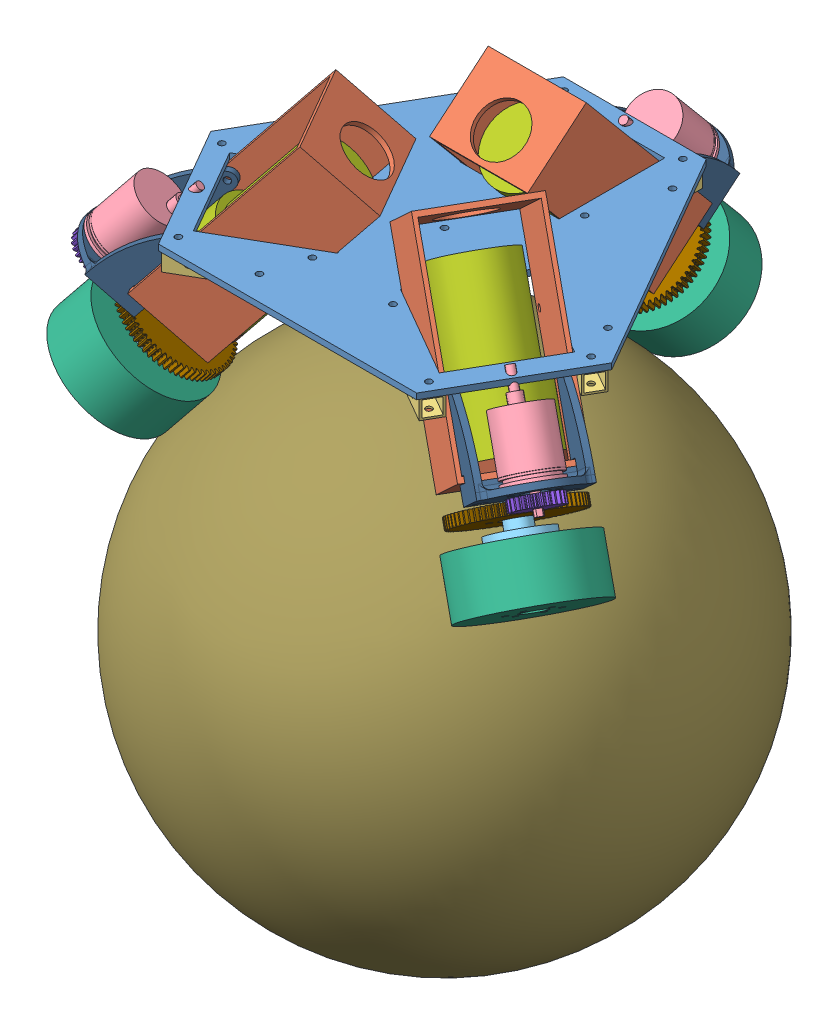
SolidWorks assembly 玉乗りロボット, configuration ﾃﾞﾌｫﾙﾄ. Lengths in mm.
Overall size (412.44 432.36 384.3).
38 component instances, 12 part files, 13 mates.
Components (placement in the parent):
- 土台1段目板-1: 土台1段目板 [ﾃﾞﾌｫﾙﾄ] at (0 175.0271 0) x (-0.5 0 -0.866025) z (0 1 0) size (204.33 176.96 3)
- 脚ユニット-1: 脚ユニット [ﾃﾞﾌｫﾙﾄ] at (4.0472 123.7086 71.2224) x (-0.55667 0.766044 -0.321394) z (0.5 0 -0.866025) size (148.1 79.92 70.5)
  - モータエンコーダ取り付け角柱-1: モータエンコーダ取り付け角柱 [ﾃﾞﾌｫﾙﾄ] at (20.22 50.0169 59.6568) x (1 0 0) z (0 -1 0) size (100 50 39)
  - 土台と脚取り付け角柱-1: 土台と脚取り付け角柱 [ﾃﾞﾌｫﾙﾄ] at (18.0757 50.5169 29.4068) x (0.766044 0.642788 0) z (0.642788 -0.766044 0) size (10 10 60)
  - 土台と脚取り付け角柱-2: 土台と脚取り付け角柱 [ﾃﾞﾌｫﾙﾄ] at (18.0757 50.5169 89.9068) x (0.766044 0.642788 0) z (0.642788 -0.766044 0) size (10 10 60)
  - E6A2_CW3C-1: E6A2_CW3C [ﾃﾞﾌｫﾙﾄ] at (-34.78 82.1169 68.6568) x (0 0 1) z (-1 0 0) size (25 25 56.5)
  - オムニ用ハブ-1: オムニ用ハブ [ﾃﾞﾌｫﾙﾄ] at (-52.28 45.5169 59.6568) x (1 0 0) z (0 -0.475862 0.87952) size (16 28 28)
  - オムニホイール-1: オムニホイール [ﾃﾞﾌｫﾙﾄ] at (-52.28 45.5169 59.6568) x (-1 0 0) z (0 -0.027652 -0.999618) size (25.6 60 60)
  - モータ_ツカサ電工-1: モータ_ツカサ電工 [ﾃﾞﾌｫﾙﾄ] at (9.22 45.5169 59.6568) x (0 0 -1) z (-1 0 0) size (43 43 101)
  - エンコーダ歯車-1: エンコーダ歯車 [デフォルト] at (-38.78 82.1169 59.6568) x (0 0.046374 -0.998924) z (1 0 0) size (22.4 22.38 5)
  - モータ伝達歯車-1: モータ伝達歯車 [アクリル切り出し] at (-41.28 45.5169 59.6568) x (0 0.999618 -0.027652) z (-1 0 0) size (53.59 53.59 5)
  - エンコーダ取付3D部品-1: エンコーダ取付3D部品 [ﾃﾞﾌｫﾙﾄ] at (-37.78 45.7169 59.6568) x (0 0 1) z (-1 0 0) size (44.6 34 47)
  - モータ取り付けアクリル板-1: モータ取り付けアクリル板 [ﾃﾞﾌｫﾙﾄ] at (-27.28 45.5169 59.6568) x (0 -0.866025 -0.5) z (1 0 0) size (43 43 5)
- 脚ユニット-2: 脚ユニット [ﾃﾞﾌｫﾙﾄ] at (59.6568 123.7086 -39.1162) x (0 0.766044 0.642788) z (-1 0 0) size (148.1 79.92 70.5)
  - モータエンコーダ取り付け角柱-1: モータエンコーダ取り付け角柱 [ﾃﾞﾌｫﾙﾄ] at (20.22 50.0169 59.6568) x (1 0 0) z (0 -1 0) size (100 50 39)
  - 土台と脚取り付け角柱-1: 土台と脚取り付け角柱 [ﾃﾞﾌｫﾙﾄ] at (18.0757 50.5169 29.4068) x (0.766044 0.642788 0) z (0.642788 -0.766044 0) size (10 10 60)
  - 土台と脚取り付け角柱-2: 土台と脚取り付け角柱 [ﾃﾞﾌｫﾙﾄ] at (18.0757 50.5169 89.9068) x (0.766044 0.642788 0) z (0.642788 -0.766044 0) size (10 10 60)
  - E6A2_CW3C-1: E6A2_CW3C [ﾃﾞﾌｫﾙﾄ] at (-34.78 82.1169 68.6568) x (0 0 1) z (-1 0 0) size (25 25 56.5)
  - オムニ用ハブ-1: オムニ用ハブ [ﾃﾞﾌｫﾙﾄ] at (-52.28 45.5169 59.6568) x (1 0 0) z (0 -0.475862 0.87952) size (16 28 28)
  - オムニホイール-1: オムニホイール [ﾃﾞﾌｫﾙﾄ] at (-52.28 45.5169 59.6568) x (-1 0 0) z (0 -0.027652 -0.999618) size (25.6 60 60)
  - モータ_ツカサ電工-1: モータ_ツカサ電工 [ﾃﾞﾌｫﾙﾄ] at (9.22 45.5169 59.6568) x (0 0 -1) z (-1 0 0) size (43 43 101)
  - エンコーダ歯車-1: エンコーダ歯車 [デフォルト] at (-38.78 82.1169 59.6568) x (0 0.046374 -0.998924) z (1 0 0) size (22.4 22.38 5)
  - モータ伝達歯車-1: モータ伝達歯車 [アクリル切り出し] at (-41.28 45.5169 59.6568) x (0 0.999618 -0.027652) z (-1 0 0) size (53.59 53.59 5)
  - エンコーダ取付3D部品-1: エンコーダ取付3D部品 [ﾃﾞﾌｫﾙﾄ] at (-37.78 45.7169 59.6568) x (0 0 1) z (-1 0 0) size (44.6 34 47)
  - モータ取り付けアクリル板-1: モータ取り付けアクリル板 [ﾃﾞﾌｫﾙﾄ] at (-27.28 45.5169 59.6568) x (0 -0.866025 -0.5) z (1 0 0) size (43 43 5)
- 脚ユニット-3: 脚ユニット [ﾃﾞﾌｫﾙﾄ] at (-63.704 123.7086 -32.1063) x (0.55667 0.766044 -0.321394) z (0.5 0 0.866025) size (148.1 79.92 70.5)
  - モータエンコーダ取り付け角柱-1: モータエンコーダ取り付け角柱 [ﾃﾞﾌｫﾙﾄ] at (20.22 50.0169 59.6568) x (1 0 0) z (0 -1 0) size (100 50 39)
  - 土台と脚取り付け角柱-1: 土台と脚取り付け角柱 [ﾃﾞﾌｫﾙﾄ] at (18.0757 50.5169 29.4068) x (0.766044 0.642788 0) z (0.642788 -0.766044 0) size (10 10 60)
  - 土台と脚取り付け角柱-2: 土台と脚取り付け角柱 [ﾃﾞﾌｫﾙﾄ] at (18.0757 50.5169 89.9068) x (0.766044 0.642788 0) z (0.642788 -0.766044 0) size (10 10 60)
  - E6A2_CW3C-1: E6A2_CW3C [ﾃﾞﾌｫﾙﾄ] at (-34.78 82.1169 68.6568) x (0 0 1) z (-1 0 0) size (25 25 56.5)
  - オムニ用ハブ-1: オムニ用ハブ [ﾃﾞﾌｫﾙﾄ] at (-52.28 45.5169 59.6568) x (1 0 0) z (0 -0.475862 0.87952) size (16 28 28)
  - オムニホイール-1: オムニホイール [ﾃﾞﾌｫﾙﾄ] at (-52.28 45.5169 59.6568) x (-1 0 0) z (0 -0.027652 -0.999618) size (25.6 60 60)
  - モータ_ツカサ電工-1: モータ_ツカサ電工 [ﾃﾞﾌｫﾙﾄ] at (9.22 45.5169 59.6568) x (0 0 -1) z (-1 0 0) size (43 43 101)
  - エンコーダ歯車-1: エンコーダ歯車 [デフォルト] at (-38.78 82.1169 59.6568) x (0 0.046374 -0.998924) z (1 0 0) size (22.4 22.38 5)
  - モータ伝達歯車-1: モータ伝達歯車 [アクリル切り出し] at (-41.28 45.5169 59.6568) x (0 0.999618 -0.027652) z (-1 0 0) size (53.59 53.59 5)
  - エンコーダ取付3D部品-1: エンコーダ取付3D部品 [ﾃﾞﾌｫﾙﾄ] at (-37.78 45.7169 59.6568) x (0 0 1) z (-1 0 0) size (44.6 34 47)
  - モータ取り付けアクリル板-1: モータ取り付けアクリル板 [ﾃﾞﾌｫﾙﾄ] at (-27.28 45.5169 59.6568) x (0 -0.866025 -0.5) z (1 0 0) size (43 43 5)
- 球-1: 球 [ﾃﾞﾌｫﾙﾄ] x (0.798586 0.538291 0.269265) z (-0.428264 0.193852 0.882616) size (250 250 250)
Mates (geometry in assembly coordinates):
- 同心円1: concentric: circle of 土台1段目板-1; circle of 脚ユニット-1/土台と脚取り付け角柱-2
- 平行1: parallel: line of 土台1段目板-1 through (87.9306 178.0271 21.6106) axis (-0.866025 0 -0.5); line of 脚ユニット-1/土台と脚取り付け角柱-2 through (48.9712 175.0271 -12.4296) axis (0.866025 0 0.5)
- 同心円2: concentric: circle of 土台1段目板-1; circle of 脚ユニット-2/土台と脚取り付け角柱-2
- 平行2: parallel: line of 土台1段目板-1 through (-25.25 178.0271 -86.9554) axis (0 0 1); line of 脚ユニット-2/土台と脚取り付け角柱-2 through (-35.25 175.0271 -36.1955) axis (0 0 -1)
- 同心円3: concentric: circle of 土台1段目板-1; circle of 脚ユニット-3/土台と脚取り付け角柱-2
- 平行3: parallel: line of 土台1段目板-1 through (-62.6806 178.0271 65.3449) axis (0.866025 0 -0.5); line of 脚ユニット-3/土台と脚取り付け角柱-2 through (-13.7212 165.0271 48.6251) axis (-0.866025 0 0.5)
- 一致1: coincident: plane of 土台1段目板-1 through (0 175.0271 0) normal (0 -1 0); plane of 脚ユニット-1/土台と脚取り付け角柱-2 through (43.9712 175.0271 -3.7694) normal (0 1 0)
- 一致2: coincident: plane of 土台1段目板-1 through (0 175.0271 0) normal (0 -1 0); plane of 脚ユニット-2/土台と脚取り付け角柱-2 through (-25.25 175.0271 -36.1955) normal (0 1 0)
- 一致3: coincident: plane of 土台1段目板-1 through (0 175.0271 0) normal (0 -1 0); plane of 脚ユニット-3/土台と脚取り付け角柱-2 through (-18.7212 175.0271 39.9649) normal (0 1 0)
- 正接1: tangent: cylinder of 脚ユニット-3/オムニホイール-1 through (-107.4256 93.3068 62.0222) axis (0.55667 0.766044 -0.321394) radius 30; sphere of 球-1
- 同心円5: concentric: sphere of 球-1; point of assembly
- 同心円6: concentric: circle of 土台1段目板-1; line of assembly
- 平行4: parallel: line of 土台1段目板-1 through (65.7665 178.0271 80) axis (-1 0 0); plane of assembly
